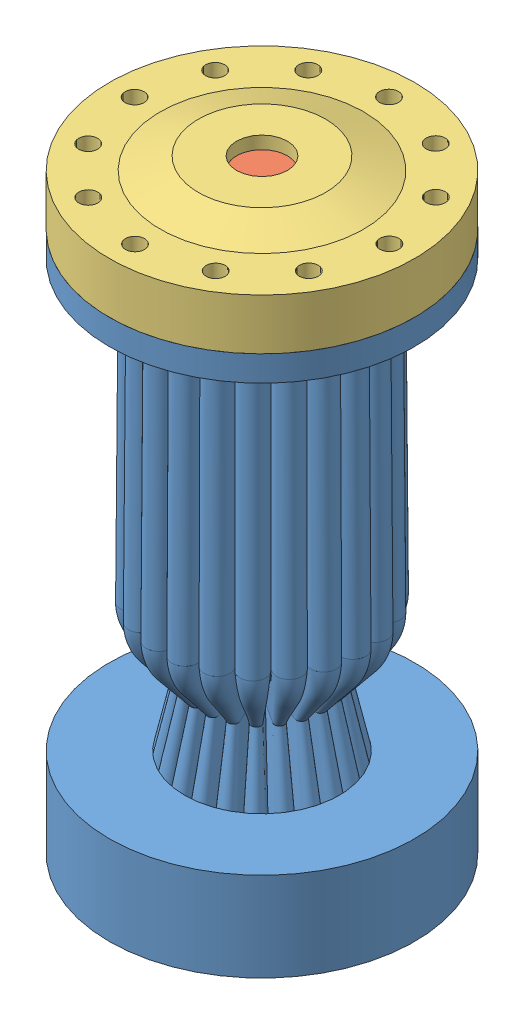
SolidWorks assembly tube cooling jacket engine, configuration Default. Lengths in mm.
Overall size (152.62 301.63 152.62).
3 component instances, 3 part files, 5 mates.
Components (placement in the parent):
- tube cooling jacket 2-1: tube cooling jacket 2 [Default] at origin size (152.4 269.88 152.4)
- impinging injector-1: impinging injector [Default] at (0 186.67 0) x (0.999707 0 -0.024225) z (0.024225 0 0.999707) size (76.2 19.05 76.2)
- dome-1: dome [Default] at (0 193.02 0) x (0.999999 0 -0.00143) z (0.00143 0 0.999999) size (152.4 31.75 152.4)
Mates (geometry in assembly coordinates):
- Coincident1: coordinate: point of tube cooling jacket 2-1
- Concentric1: concentric aligned: cylinder of tube cooling jacket 2-1 through (0 212.7336 0) axis (0 1 0) radius 76.2; cylinder of impinging injector-1 through (0 205.72 0) axis (0 1 0) radius 38.1
- Coincident3: coincident anti-aligned: plane of tube cooling jacket 2-1 through (-76.2 193.02 0) normal (0 1 0); plane of impinging injector-1 through (-34.9148 193.02 0.8461) normal (0 -1 0)
- Concentric2: concentric anti-aligned: cylinder of tube cooling jacket 2-1 through (0 212.7336 0) axis (0 1 0) radius 76.2; cylinder of dome-1 through (0 191.4325 0) axis (0 -1 0) radius 76.2
- Coincident4: coincident anti-aligned: plane of tube cooling jacket 2-1 through (-76.2 193.02 0) normal (0 1 0); plane of dome-1 through (-55.1306 193.02 0.0788) normal (0 -1 0)
